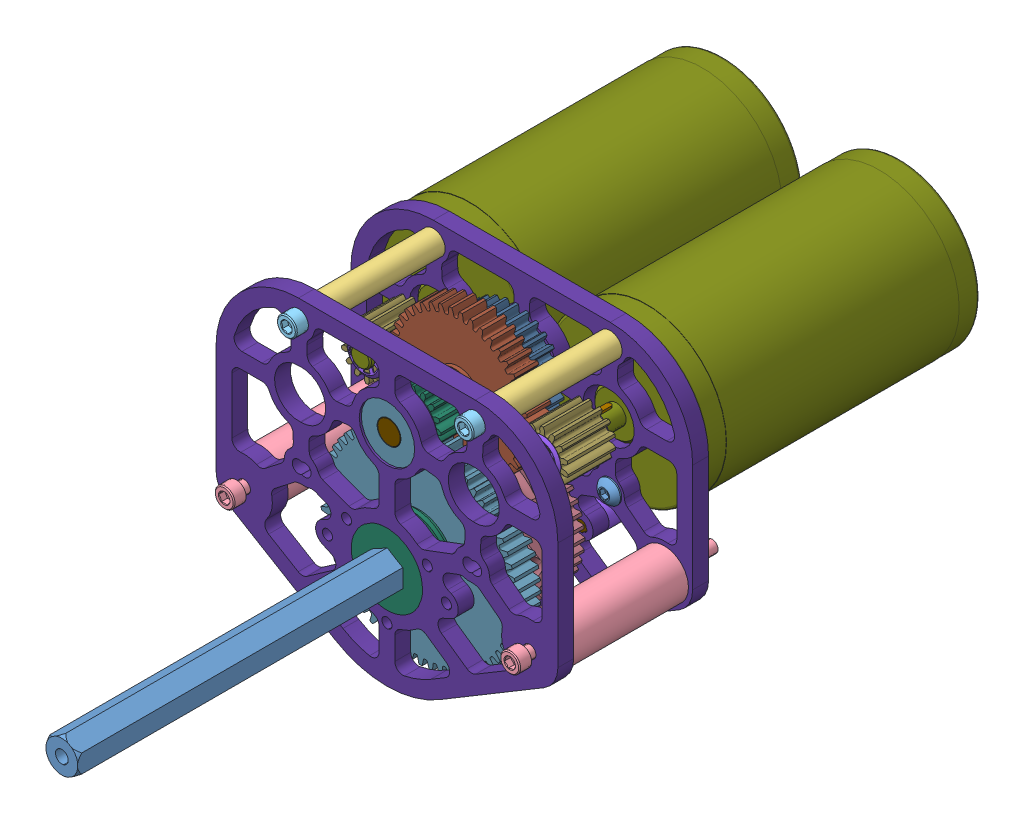
SolidWorks assembly WCP DS Gearbox, configuration Default. Lengths in mm.
Overall size (138.74 141.15 305.07).
67 component instances, 42 part files, 0 mates.
Components (placement in the parent):
- 217-2778-001 Rev2_NCQ8A075-050M_1-1: 217-2778-001 Rev2_NCQ8A075-050M_1 [Default] at (0 -47.0408 -61.087) x (-0.724709 0.689055 0) z (0 0 1) size (31.75 33.34 52.54)
  - 217-2778-NCQ8A075-050M_NCQ8 Tube_075A_1-1: 217-2778-NCQ8A075-050M_NCQ8 Tube_075A_1 [Default] at origin size (31.75 33.34 26.92)
  - 217-2778-NCQ8A075-050M_NCQ8 Rod_075M_1-1: 217-2778-NCQ8A075-050M_NCQ8 Rod_075M_1 [Default] at (0 0 3.8126) x (-1 0 0) z (0 0 1) size (18.95 18.95 35.27)
  - 217-2778-NCQ8A075-050M_Snap Ring_075_1-1: 217-2778-NCQ8A075-050M_Snap Ring_075_1 [Default] at (0 0 10.362) size (21 20.74 0.97)
- 217-3195-200 Rev1_1-1: 217-3195-200 Rev1_1 [Default] at (0 -47.0408 -22.8339) x (1 0 0) z (0 0 -1) size (20.44 19.56 22.68)
  - 217-3195-010 Rev1_1-1: 217-3195-010 Rev1_1 [Default] x (-1 0 0) z (0 0 1) size (19.61 11.78 22.68)
  - 217-3195-010 Rev1_1-2: 217-3195-010 Rev1_1 [Default] at origin size (19.61 11.78 22.68)
  - 217-2778-NCQ8A075-050M_1032_Nut_90545A111_1-1: 217-2778-NCQ8A075-050M_1032_Nut_90545A111_1 [Default] at (0 0 2.5527) x (-0.5 0.866025 0) z (0 0 1) size (9.53 11 3.39)
  - 91251A107_91251A107-1: 91251A107_91251A107 [Default] at (-7.4168 -4.9375 -0.635) x (1 0 0) z (0 -1 0) size (4.65 4.65 10.79)
  - 91251A107_91251A107-2: 91251A107_91251A107 [Default] at (7.4168 4.9375 -0.635) x (-0.837169 0 -0.546944) z (0 1 0) size (4.65 4.65 10.79)
- 217-3423-005 Rev1_1-1: 217-3423-005 Rev1_1 [Default] at (0 -47.0408 -46.0375) size (57.15 38.1 3.17)
- 217-3423-006 Rev1_1-1: 217-3423-006 Rev1_1 [Default] at (23.8125 -47.0408 -23.8125) x (0 0 1) z (0.999923 -0.012371 0) size (41.27 9.53 9.53)
- 217-3423-008 Rev1_1-1: 217-3423-008 Rev1_1 [Default] at (0 -47.0408 -11.5182) x (0 1 0) z (0 0 1) size (7.14 7.14 57.15)
- 217-3423-009 Rev3_1-1: 217-3423-009 Rev3_1 [Default] at (0 -47.0408 32.0872) x (-1 0 0) z (0 0 1) size (26.99 26.99 12.7)
- 217-3423-006 Rev1_1-2: 217-3423-006 Rev1_1 [Default] at (-23.8125 -47.0408 -23.8125) x (0 0 1) z (-0.442788 -0.896626 0) size (41.27 9.53 9.53)
- 217-3489_1-1: 217-3489_1 [Default] at (0 -47.0408 -16.3887) x (0 0 1) z (0.218426 -0.975853 0) size (4.77 12.7 12.7)
- 217-2428-027 Rev1_97414A630_1-1: 217-2428-027 Rev1_97414A630_1 [Default] at (0 -47.0408 -19.0874) x (0 0 1) z (-0.952629 0.304134 0) size (0.64 5.89 7.9)
- SBS1_SBS-0632-0250-1: SBS1_SBS-0632-0250 [Default] at (0 -31.5468 -42.5958) x (0 0 -1) z (0.950975 0.309268 0) size (8.57 6.68 6.65)
- SBS1_SBS-0632-0250-2: SBS1_SBS-0632-0250 [Default] at (0 -62.5348 -42.5958) x (0 0 -1) z (0.950975 0.309268 0) size (8.57 6.68 6.65)
- 217-2733_1-1: 217-2733_1 [Default] at (0 0 4.7625) x (0 0 -1) z (0.79471 -0.606989 0) size (7.11 24.61 24.61)
- 217-2733_1-2: 217-2733_1 [Default] at (0 0 49.2125) x (0 0 1) z (-0.575096 -0.818086 0) size (7.11 24.61 24.61)
- 217-2734_1-1: 217-2734_1 [Default] at (0 -47.0408 57.15) x (-0.033107 -0.999452 0) z (0.999452 -0.033107 0) size (31.12 7.94 31.12)
- 217-2734_1-2: 217-2734_1 [Default] at (0 -47.0408 39.6557) x (-0.405868 -0.913932 0) z (-0.913932 0.405868 0) size (31.12 7.94 31.12)
- 217-2743_1-1: 217-2743_1 [Default] at (0 -47.0408 7.9057) x (0 0 -1) z (0.947967 0.31837 0) size (7.94 28.57 28.57)
- 217-2731_1-1: 217-2731_1 [Default] at (0 -47.0408 3.175) x (-0.539745 -0.841828 0) z (0.841828 -0.539745 0) size (31.12 7.94 31.12)
- 217-3421-007 Rev1_1-1: 217-3421-007 Rev1_1 [Default] at (23.8125 -47.0408 -47.625) x (0 0 1) z (0.593474 0.804853 0) size (55.85 7.92 7.92)
- 217-3421-007 Rev1_1-2: 217-3421-007 Rev1_1 [Default] at (-23.8125 -47.0408 -47.625) x (0 0 1) z (-0.971026 -0.238972 0) size (55.85 7.92 7.92)
- 217-3421-009 Rev1_1-1: 217-3421-009 Rev1_1 [Default] at (35.4115 -29.21 3.175) x (0 0 -1) z (0.987344 0.158596 0) size (15.78 9.26 9.25)
- 217-3421-009 Rev1_1-2: 217-3421-009 Rev1_1 [Default] at (-35.4115 -29.21 3.175) x (0 0 -1) z (0.987344 0.158596 0) size (15.78 9.26 9.25)
- 217-3421-010 Rev1_1-1: 217-3421-010 Rev1_1 [Default] at (57.15 -47.0408 -3.175) x (0.898322 -0.439338 0) z (0.439338 0.898322 0) size (9.53 6.13 11)
- 217-3421-010 Rev1_1-2: 217-3421-010 Rev1_1 [Default] at (-57.15 -47.0408 -3.175) x (0.982822 -0.184556 0) z (0.184556 0.982822 0) size (9.53 6.13 11)
- 217-3421-011 Rev2_97633A200_1-1: 217-3421-011 Rev2_97633A200_1 [Default] at (0 -47.0408 -5.2388) x (0 0 -1) z (0.95045 -0.310879 0) size (0.89 16.1 14.34)
- 217-3422-006 Rev1-1: 217-3422-006 Rev1 [Default] at (57.15 -47.0408 60.325) x (0 0 -1) z (-0.733896 -0.679262 0) size (81.25 7.92 7.92)
- 217-3422-006 Rev1-2: 217-3422-006 Rev1 [Default] at (-57.15 -47.0408 60.325) x (0 0 -1) z (0.0516 0.998668 0) size (81.25 7.92 7.92)
- 217-3423-012 Rev1-1: 217-3423-012 Rev1 [Default] at (35.4115 21.59 57.15) x (0 0 -1) z (0.651943 -0.758268 0) size (71.73 7.92 7.92)
- 217-3423-012 Rev1-2: 217-3423-012 Rev1 [Default] at (-35.4115 21.59 57.15) x (0 0 -1) z (0.658015 -0.753004 0) size (71.73 7.92 7.92)
- 217-3423-014 Rev1_1-1: 217-3423-014 Rev1_1 [Default] at (-13.4938 -47.0408 32.0872) x (0 0.867283 -0.497815) z (-1 0 0) size (4.65 4.65 26.79)
- 217-3423-016 Rev1_1-1: 217-3423-016 Rev1_1 [Default] at (0 -65.6939 -4.7625) x (0 0 1) z (-0.596583 -0.802551 0) size (11.03 9.26 9.25)
- 217-3423-016 Rev1_1-2: 217-3423-016 Rev1_1 [Default] at (-16.1541 -37.7142 -4.7625) x (0 0 1) z (-0.596583 -0.802551 0) size (11.03 9.26 9.25)
- 217-3423-016 Rev1_1-3: 217-3423-016 Rev1_1 [Default] at (16.1541 -37.7142 -4.7625) x (0 0 1) z (-0.596583 -0.802551 0) size (11.03 9.26 9.25)
- 217-2614-002_98430A132_1-1: 217-2614-002_98430A132_1 [Default] at (35.4115 -3.81 9.9695) x (0 0 1) z (-0.864814 -0.502092 0) size (1.2 14.83 14.83)
- 217-2614-002_98430A132_1-2: 217-2614-002_98430A132_1 [Default] at (35.4115 -3.81 31.1531) x (0 0 -1) z (0.980787 -0.195081 0) size (1.2 14.83 14.83)
- 217-2614-002_98430A132_1-3: 217-2614-002_98430A132_1 [Default] at (-35.4115 -3.81 31.1531) x (0 0 -1) z (-0.821319 -0.570469 0) size (1.2 14.83 14.83)
- 217-2614-002_98430A132_1-4: 217-2614-002_98430A132_1 [Default] at (-35.4115 -3.81 9.9695) x (0 0 1) z (-0.844607 -0.535387 0) size (1.2 14.83 14.83)
- 217-2761-001 rev1_1-1: 217-2761-001 rev1_1 [Default] at (-35.4115 -0.01 12.925) size (2 2 20)
- 217-2761-001 rev1_1-2: 217-2761-001 rev1_1 [Default] at (35.4115 -0.01 12.925) size (2 2 20)
- 217-3210-001 Rev1_30t_1-1: 217-3210-001 Rev1_30t_1 [Default] at (0 0 11.0871) x (0.988842 0.148971 0) z (0 0 1) size (41.01 41.12 12.65)
- 217-3215-001 Rev1_42t_1-1: 217-3215-001 Rev1_42t_1 [Default] at (0 0 23.7363) x (0.8078 -0.589457 0) z (0 0 1) size (56.22 56.3 12.65)
- 217-3414-001 Rev1_14t Steel Pinion_1-1: 217-3414-001 Rev1_14t Steel Pinion_1 [Default] at (-35.4115 -3.81 20.5613) x (0.914095 -0.405501 0) z (0 0 1) size (20.32 20.6 19.05)
- 217-3414-001 Rev1_14t Steel Pinion_1-2: 217-3414-001 Rev1_14t Steel Pinion_1 [Default] at (35.4115 -3.81 20.5613) x (0.999225 0.039352 0) z (0 0 1) size (20.32 20.6 19.05)
- 217-3418-001 Rev2_44t_1-1: 217-3418-001 Rev2_44t_1 [Default] at (0 -47.0408 11.922) x (0.876071 -0.482182 0) z (0 0 1) size (58.67 58.67 9.53)
- 217-3420-001 Rev2_60t_1-1: 217-3420-001 Rev2_60t_1 [Default] at (0 -47.0408 39.6082) x (-0.829017 -0.559223 0) z (0 0 -1) size (78.95 78.95 9.53)
- 217-3100-001_14t_1-1: 217-3100-001_14t_1 [Default] at (0 0 39.5859) x (0.526969 0.849885 0) z (0 0 1) size (20.32 20.6 12.7)
- 217-2000_1-1: 217-2000_1 [Default] at (35.4115 -3.81 -3.175) x (0 0 -1) z (1 0 0) size (150.2 64.01 64.01)
- 217-2000_1-2: 217-2000_1 [Default] at (-35.4115 -3.81 -3.175) x (0 0 -1) z (1 0 0) size (150.2 64.01 64.01)
- 217-3423-001 Rev1_Default_As Machined__1-1: 217-3423-001 Rev1_Default_As Machined__1 [Default] at origin size (136.86 116.89 6.35)
- 217-3423-001 Rev1_Default_As Machined__1-2: 217-3423-001 Rev1_Default_As Machined__1 [Default] at (0 0 53.975) x (-1 0 0) z (0 0 -1) size (136.86 116.89 6.35)
- 217-3423-002 Rev1-1: 217-3423-002 Rev1 [Default] at (0 0 26.9875) x (0.576816 0.816874 0) z (0 0 1) size (11 9.53 58.74)
- 217-3423-003 Rev1_1-1: 217-3423-003 Rev1_1 [Default] at (0 -47.0408 25.7651) x (0 -1 0) z (0 0 1) size (18.33 15.88 194.69)
- 217-3423-004 Rev1_1-1: 217-3423-004 Rev1_1 [Default] at (0 -47.0408 3.556) size (19.05 19.05 0.76)
- 217-3423-010 Rev1-1: 217-3423-010 Rev1 [Default] at (35.4115 21.59 26.9875) x (-0.522062 0.852908 0) z (0 0 1) size (9.53 9.53 47.62)
- 217-3423-010 Rev1-2: 217-3423-010 Rev1 [Default] at (-35.4115 21.59 26.9875) size (9.53 9.53 47.62)
- 217-3423-011 Rev1-1: 217-3423-011 Rev1 [Default] at (-57.15 -47.0408 26.9875) size (19.13 19.13 53.98)
- 217-3423-011 Rev1-2: 217-3423-011 Rev1 [Default] at (57.15 -47.0408 26.9875) x (0.850589 -0.525831 0) z (0 0 1) size (19.13 19.13 53.98)
- 217-3256-001 Rev1_1-1: 217-3256-001 Rev1_1 [Default] at (0 0 31.6484) x (0.524203 -0.851594 0) z (0 0 1) size (15.88 15.88 3.17)
- 217-3256-001 Rev1_1-2: 217-3256-001 Rev1_1 [Default] at (0 0 47.625) x (-0.224279 -0.974525 0) z (0 0 1) size (15.88 15.88 3.17)
- 217-3257-001 Rev1_1-1: 217-3257-001 Rev1_1 [Default] at (0 -47.0408 48.4188) size (19.5 19.5 1.59)
